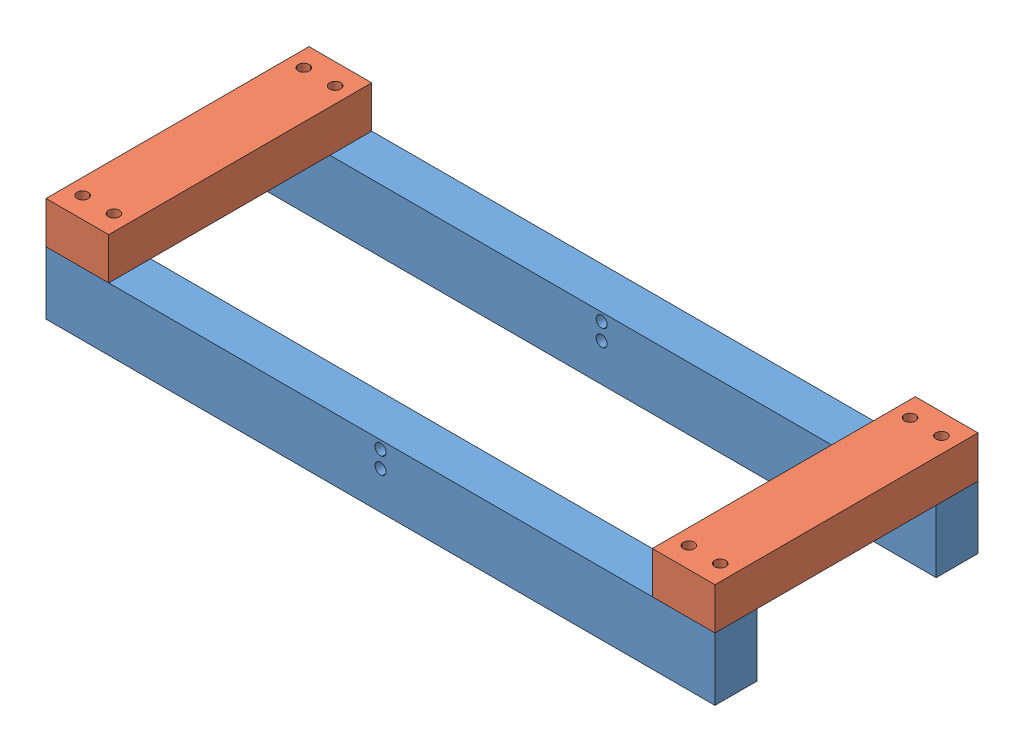
SolidWorks assembly assembly_jig, configuration Default. Lengths in mm.
Overall size (406.4 63.5 159.77).
4 component instances, 2 part files, 8 mates.
Components (placement in the parent):
- assembly_jig_side-1: assembly_jig_side [Default] at origin size (406.4 38.1 25.4)
- assembly_jig_top-1: assembly_jig_top [Default] at (-165.1 50.8 -67.183) x (0 0 -1) z (0 1 0) size (152.4 38.1 25.4)
- assembly_jig_side-2: assembly_jig_side [Default] at (0 0 -134.366) size (406.4 38.1 25.4)
- assembly_jig_top-2: assembly_jig_top [Default] at (203.2 50.8 -67.183) x (0 0 -1) z (0 1 0) size (152.4 38.1 25.4)
Mates (geometry in assembly coordinates):
- Coincident1: coincident anti-aligned: plane of assembly_jig_side-1 through (0 38.1 0) normal (0 1 0); plane of assembly_jig_top-1 through (-203.2 38.1 9.017) normal (0 -1 0)
- Coincident2: coincident anti-aligned: plane of assembly_jig_top-1 through (-203.2 38.1 9.017) normal (0 -1 0); plane of assembly_jig_side-2 through (0 38.1 -134.366) normal (0 1 0)
- Coincident3: coincident anti-aligned: plane of assembly_jig_side-1 through (0 38.1 0) normal (0 1 0); plane of assembly_jig_top-2 through (165.1 38.1 9.017) normal (0 -1 0)
- Concentric4: concentric aligned: cylinder of assembly_jig_side-1 through (193.675 38.1 0) axis (0 1 0) radius 3.175; cylinder of assembly_jig_top-2 through (193.675 63.5 0) axis (0 1 0) radius 3.3782
- Concentric5: concentric aligned: cylinder of assembly_jig_side-2 through (193.675 38.1 -134.366) axis (0 1 0) radius 3.175; cylinder of assembly_jig_top-2 through (193.675 63.5 -134.366) axis (0 1 0) radius 3.3782
- Concentric6: concentric aligned: cylinder of assembly_jig_top-1 through (-193.675 63.5 -134.366) axis (0 1 0) radius 3.3782; cylinder of assembly_jig_side-2 through (-193.675 38.1 -134.366) axis (0 1 0) radius 3.175
- Concentric7: concentric aligned: cylinder of assembly_jig_side-1 through (-193.675 38.1 0) axis (0 1 0) radius 3.175; cylinder of assembly_jig_top-1 through (-193.675 63.5 0) axis (0 1 0) radius 3.3782
- Concentric8: concentric aligned: cylinder of assembly_jig_top-1 through (-174.625 63.5 -134.366) axis (0 1 0) radius 3.3782; cylinder of assembly_jig_side-2 through (-174.625 38.1 -134.366) axis (0 1 0) radius 3.175
